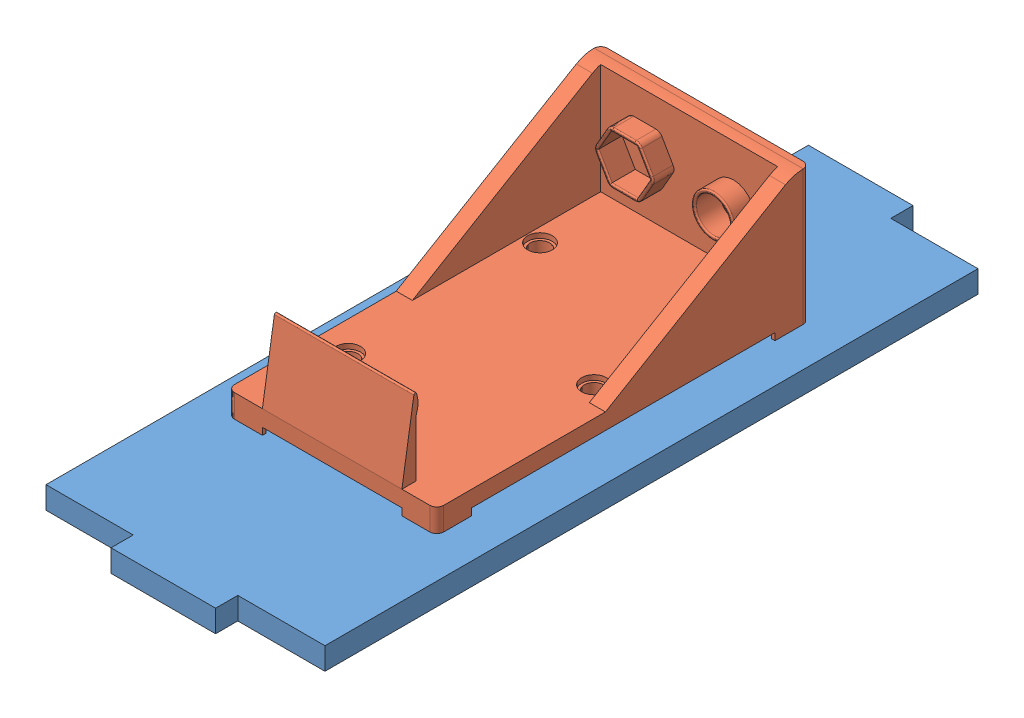
SolidWorks assembly Battery mount part with Battery mount, configuration Default. Lengths in mm.
Overall size (40 22.49 100).
2 component instances, 2 part files, 3 mates.
Components (placement in the parent):
- Battery mount part-1: Battery mount part [Default] at (31.1756 54.1099 78.6973) size (40 3.18 100)
- 9V Battery Holder-1: 9V Battery Holder [Default] at (30.566 58.2899 77.1275) x (0 0 1) z (0 1 0) size (53.5 30 19.31)
Mates (geometry in assembly coordinates):
- Coincident1: coincident anti-aligned: plane of Battery mount part-1 through (31.1756 57.2899 78.6973) normal (0 1 0); plane of 9V Battery Holder-1 through (44.566 57.2899 102.8775) normal (0 -1 0)
- Parallel1: parallel: plane of Battery mount part-1 through (11.1756 57.2899 128.6973) normal (-1 0 0); line of 9V Battery Holder-1 through (15.566 58.2899 55.3775) axis (0 0 1)
- Parallel2: parallel aligned: plane of Battery mount part-1 through (51.1756 57.2899 28.6973) normal (0 0 -1); plane of 9V Battery Holder-1 through (15.566 60.6013 50.3775) normal (0 0 -1)
